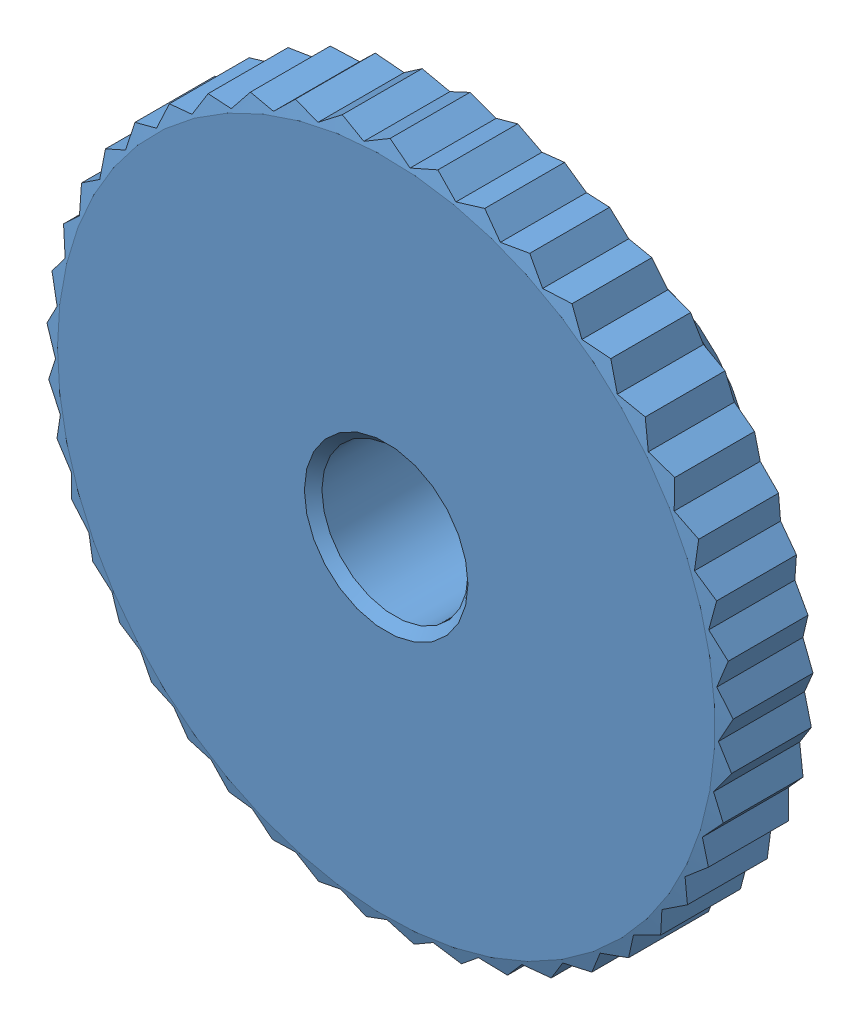
SolidWorks assembly GEABP0_5_45_3_B_5, configuration Default. Lengths in mm.
Overall size (23.49 23.47 8).
2 component instances, 2 part files, 0 mates.
Components (placement in the parent):
- GEABP0_5_45_3_B_5_b-1: GEABP0_5_45_3_B_5_b [Default] x (-1 0 0) z (0 0 -1) size (23.49 23.47 8)
- Hexagon_socket_set_screw_with_flat_point_DIN_913___M3x3-1: Hexagon_socket_set_screw_with_flat_point_DIN_913___M3x3 [Default] at (0 5.5 -5.5) x (0 -1 0) z (1 0 0) size (3 3 3)
